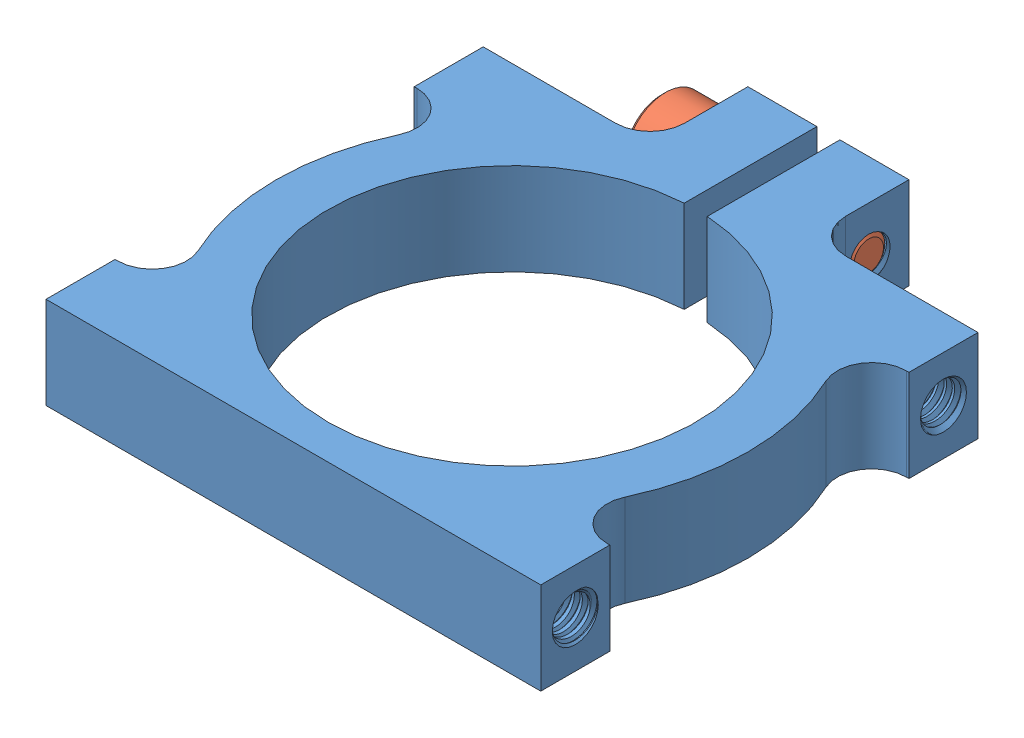
SolidWorks assembly gobilda-32mm-motor-clamp-1401-0043-0032, configuration Default. Lengths in mm.
Overall size (43.27 8.04 47.02).
2 component instances, 2 part files, 0 mates.
Components (placement in the parent):
- 1401-0043-0032-1: 1401-0043-0032 [Default] at (0.7931 12.12 -4.4026) size (43.27 8 46.5)
- 2800-0004-0014_90128A207-1: 2800-0004-0014_90128A207 [Default] at (7.7931 12.12 -28.4026) x (0 0.161804 -0.986823) z (1 0 0) size (7 7 18.17)
